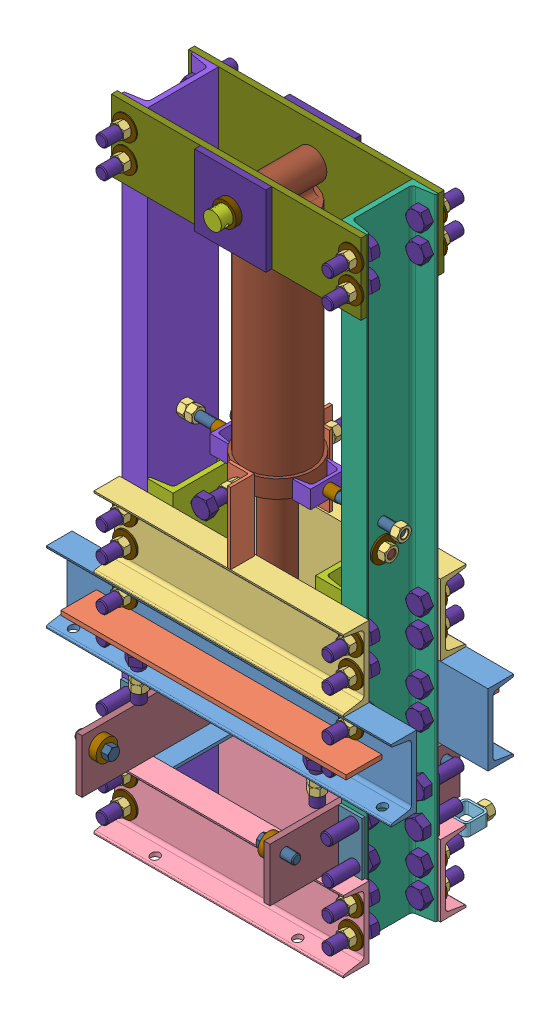
SolidWorks assembly Assem3, configuration Default. Lengths in mm.
Overall size (736.6 1346.2 447.6).
222 component instances, 36 part files, 6 mates.
Components (placement in the parent):
- 01-019-00-0_test-2: 01-019-00-0_test [Default] at (-593.8061 -294.0472 81.4777) size (736.6 1346.2 447.6)
  - 01-013-00-0-1: 01-013-00-0 [Default] at origin size (736.6 169.29 87.3)
    - 01-011-00-0-1: 01-011-00-0 [Default] at origin size (736.6 152.4 54.79)
    - 01-012-00-0-1: 01-012-00-0 [Default] at (-304.8 -4.7625 16.2941) size (609.6 9.53 76.2)
    - hex nut_ai-1: hex nut_ai [HNUT 0.7500-10-D-C] at (190.5 -93.091 -7.5311) x (1 0 0) z (0 -1 0) size (28.57 33 16.89)
    - hex nut_ai-2: hex nut_ai [HNUT 0.7500-10-D-C] at (-190.5 -93.091 -7.5311) x (1 0 0) z (0 -1 0) size (28.57 33 16.89)
  - 01-016-00-0-1: 01-016-00-0 [Default] at (0 -330.2 0) size (533.4 153.99 122.48)
    - 01-014-00-0-2: 01-014-00-0 [Default] at origin size (533.4 152.4 54.79)
    - 01-005-00-0-1: 01-005-00-0 [Default] at (-215.9 63.5 -27.3939) x (0 0 -1) z (0 1 0) size (67.69 50.8 28.57)
      - tube square_ai-1: tube square_ai [PreviewCfg] at origin size (50.8 50.8 25.4)
      - hex nut_ai-1: hex nut_ai [HNUT 0.7500-10-D-C] at (67.691 31.75 0) x (0 0 -1) z (1 0 0) size (28.57 33 16.89)
    - 01-005-00-0-3: 01-005-00-0 [Default] at (215.9 63.5 -27.3939) x (0 0 -1) z (0 -1 0) size (67.69 50.8 28.57)
      - tube square_ai-1: tube square_ai [PreviewCfg] at origin size (50.8 50.8 25.4)
      - hex nut_ai-1: hex nut_ai [HNUT 0.7500-10-D-C] at (67.691 31.75 0) x (0 0 -1) z (1 0 0) size (28.57 33 16.89)
  - 01-014-00-0-6: 01-014-00-0 [Default] at (0 -330.2 207.1878) x (-1 0 0) z (0 0 -1) size (533.4 152.4 54.79)
  - 01-116-00-0-1: 01-116-00-0 [Default] at (234.5817 266.7 103.5939) x (0 -1 0) z (-1 0 0) size (1346.2 152.4 109.58)
    - 01-115-00-0-1: 01-115-00-0 [Default] at origin size (1346.2 152.4 54.79)
    - hex nut_ai-1: hex nut_ai [HNUT 0.7500-10-D-C] at (-82.55 0 44.2849) size (28.57 33 16.89)
    - 01-034-00-0-1: 01-034-00-0 [Default] at (177.8 0 54.7878) size (330.2 152.4 54.79)
  - 01-114-00-0-1: 01-114-00-0 [Default] at (-234.5817 266.7 103.5939) x (0 -1 0) z (1 0 0) size (1346.2 152.4 109.58)
    - 01-015-00-0-2: 01-015-00-0 [Default] at origin size (1346.2 152.4 54.79)
    - hex nut_ai-1: hex nut_ai [HNUT 0.7500-10-D-C] at (-82.55 0 44.2849) size (28.57 33 16.89)
    - 01-034-00-0-1: 01-034-00-0 [Default] at (177.8 0 54.7878) size (330.2 152.4 54.79)
  - 01-013-00-0-2: 01-013-00-0 [Default] at (0 0 207.1878) x (-1 0 0) z (0 0 -1) size (736.6 169.29 87.3)
    - 01-011-00-0-1: 01-011-00-0 [Default] at origin size (736.6 152.4 54.79)
    - 01-012-00-0-1: 01-012-00-0 [Default] at (-304.8 -4.7625 16.2941) size (609.6 9.53 76.2)
    - hex nut_ai-1: hex nut_ai [HNUT 0.7500-10-D-C] at (190.5 -93.091 -7.5311) x (1 0 0) z (0 -1 0) size (28.57 33 16.89)
    - hex nut_ai-2: hex nut_ai [HNUT 0.7500-10-D-C] at (-190.5 -93.091 -7.5311) x (1 0 0) z (0 -1 0) size (28.57 33 16.89)
  - RM3-2RS-1: RM3-2RS [Default] at (173.0078 -171.45 -42.4561) x (1 0 0) z (0 -0.000451 1) size (15.88 50.64 50.64)
  - RM3-2RS-2: RM3-2RS [Default] at (173.0078 -171.45 300.4439) x (1 0 0) z (0 -0.000451 1) size (15.88 50.64 50.64)
  - hex bolt_am_Smaller-6: hex bolt_am_Smaller [PreviewCfg] at (158.0078 -171.45 -42.4561) size (75 27.71 24)
  - hex bolt_am_Smaller-7: hex bolt_am_Smaller [PreviewCfg] at (158.0078 -171.45 300.4439) size (75 27.71 24)
  - RM3-2RS-3: RM3-2RS [Default] at (-173.0078 -171.45 -42.4561) x (-1 0 0) z (0 0.924397 0.381433) size (15.88 50.64 50.64)
  - hex bolt_am_Smaller-8: hex bolt_am_Smaller [PreviewCfg] at (-158.0078 -171.45 300.4439) x (-1 0 0) z (0 -0.23868 0.971098) size (75 27.71 24)
  - hex bolt_am_Smaller-9: hex bolt_am_Smaller [PreviewCfg] at (-158.0078 -171.45 -42.4561) x (-1 0 0) z (0 0.924225 0.381849) size (75 27.71 24)
  - RM3-2RS-4: RM3-2RS [Default] at (-173.0078 -171.45 300.4439) x (-1 0 0) z (0 0.668301 -0.743891) size (15.88 50.64 50.64)
  - 01-039-00-0-1: 01-039-00-0 [Default] at (-5.0705 831.85 103.5939) x (-1 0 0) z (0 0 1) size (254 946.15 152.4)
    - PMC-21012-1: PMC-21012 [Default] at origin size (158.75 946.15 152.4)
    - 01-035-00-0-1: 01-035-00-0 [Default] at (-127 857.25 50.8) size (254 25.4 101.6)
    - 01-040-00-0-1: 01-040-00-0 [Default] at (57.15 831.85 -31.75) x (0 0 1) z (-1 0 0) size (63.5 25.4 25.4)
    - 01-040-00-0-2: 01-040-00-0 [Default] at (-57.15 831.85 31.75) x (0 0 -1) z (1 0 0) size (63.5 25.4 25.4)
    - hex nut_ai-1: hex nut_ai [HNUT 0.7500-10-D-C] at (-112.7125 840.359 -42.5511) x (1 0 0) z (0 -1 0) size (28.57 33 16.89)
    - 01-120-00-0-1: 01-120-00-0 [Default] at (-44.45 850.9 0) x (0 -1 0) z (0 0 1) size (38.1 88.9 38.1)
  - 01-038-00-0-1: 01-038-00-0 [Default] at (-157.4705 -76.2 179.7939) size (304.8 82.55 152.4)
    - 01-036-00-0-1: 01-036-00-0 [Default] at origin size (304.8 25.4 152.4)
    - 01-037-00-0-1: 01-037-00-0 [Default] at (50.8 19.05 -76.2) size (19.05 63.5 19.05)
    - 01-037-00-0-2: 01-037-00-0 [Default] at (254 19.05 -76.2) size (19.05 63.5 19.05)
  - hex bolt_ai-1: hex bolt_ai [PreviewCfg] at (-190.5 -39.37 214.7189) x (0 -1 0) z (1 0 0) size (93.98 43.99 38.1)
  - hex bolt_ai-2: hex bolt_ai [PreviewCfg] at (190.5 -39.37 214.7189) x (0 -1 0) z (1 0 0) size (93.98 43.99 38.1)
  - hex bolt_ai-3: hex bolt_ai [PreviewCfg] at (190.5 -39.37 -7.5311) x (0 -1 0) z (1 0 0) size (93.98 43.99 38.1)
  - hex bolt_ai-4: hex bolt_ai [PreviewCfg] at (-190.5 -39.37 -7.5311) x (0 -1 0) z (1 0 0) size (93.98 43.99 38.1)
  - hex bolt_ai-5: hex bolt_ai [PreviewCfg] at (241.3 -300.0375 56.4658) x (0 0 -1) z (0 1 0) size (93.98 43.99 38.1)
  - hex nut_ai-3: hex nut_ai [HNUT 0.7500-10-D-C] at (241.3 -300.0375 12.5349) x (0.998531 -0.05419 0) z (0 0 1) size (28.57 33 16.89)
  - WASHER 0.7500-WIDE-3: WASHER 0.7500-WIDE [Default] at (241.3 -300.0375 12.5349) size (50.8 50.8 3.76)
  - WASHER 0.7500-WIDE-32: WASHER 0.7500-WIDE [Default] at (241.3 -360.3625 12.5349) size (50.8 50.8 3.76)
  - hex nut_ai-28: hex nut_ai [HNUT 0.7500-10-D-C] at (241.3 -360.3625 12.5349) size (28.57 33 16.89)
  - hex bolt_ai-33: hex bolt_ai [PreviewCfg] at (241.3 -360.3625 56.4658) x (0 0 -1) z (0.005072 0.999987 0) size (93.98 43.99 38.1)
  - WASHER 0.7500-WIDE-34: WASHER 0.7500-WIDE [Default] at (241.3 -30.1625 12.5349) size (50.8 50.8 3.76)
  - hex nut_ai-30: hex nut_ai [HNUT 0.7500-10-D-C] at (241.3 -30.1625 -4.3561) x (0.923728 0.383049 0) z (0 0 -1) size (28.57 33 16.89)
  - hex bolt_ai-35: hex bolt_ai [PreviewCfg] at (241.3 -30.1625 56.4658) x (0 0 -1) z (0 1 0) size (93.98 43.99 38.1)
  - hex nut_ai-32: hex nut_ai [HNUT 0.7500-10-D-C] at (241.3 30.1625 -4.3561) x (0.923728 0.383049 0) z (0 0 -1) size (28.57 33 16.89)
  - WASHER 0.7500-WIDE-36: WASHER 0.7500-WIDE [Default] at (241.3 30.1625 12.5349) size (50.8 50.8 3.76)
  - hex bolt_ai-37: hex bolt_ai [PreviewCfg] at (241.3 30.1625 56.4658) x (0 0 -1) z (0 1 0) size (93.98 43.99 38.1)
  - hex nut_ai-34: hex nut_ai [HNUT 0.7500-10-D-C] at (241.3 122.2375 -4.3561) x (0.923728 0.383049 0) z (0 0 -1) size (28.57 33 16.89)
  - hex bolt_ai-39: hex bolt_ai [PreviewCfg] at (241.3 122.2375 56.4658) x (0 0 -1) z (0 1 0) size (93.98 43.99 38.1)
  - hex nut_ai-36: hex nut_ai [HNUT 0.7500-10-D-C] at (241.3 182.5625 -4.3561) x (0.923728 0.383049 0) z (0 0 -1) size (28.57 33 16.89)
  - WASHER 0.7500-WIDE-38: WASHER 0.7500-WIDE [Default] at (241.3 182.5625 12.5349) size (50.8 50.8 3.76)
  - hex bolt_ai-41: hex bolt_ai [PreviewCfg] at (241.3 182.5625 56.4658) x (0 0 -1) z (0 1 0) size (93.98 43.99 38.1)
  - WASHER 0.7500-WIDE-40: WASHER 0.7500-WIDE [Default] at (241.3 122.2375 12.5349) size (50.8 50.8 3.76)
  - hex nut_ai-38: hex nut_ai [HNUT 0.7500-10-D-C] at (241.3 833.4375 -4.3561) x (0.923728 0.383049 0) z (0 0 -1) size (28.57 33 16.89)
  - hex bolt_ai-43: hex bolt_ai [PreviewCfg] at (241.3 833.4375 56.4658) x (0 0 -1) z (0 1 0) size (93.98 43.99 38.1)
  - hex nut_ai-40: hex nut_ai [HNUT 0.7500-10-D-C] at (241.3 893.7625 -4.3561) x (0.923728 0.383049 0) z (0 0 -1) size (28.57 33 16.89)
  - WASHER 0.7500-WIDE-42: WASHER 0.7500-WIDE [Default] at (241.3 893.7625 12.5349) size (50.8 50.8 3.76)
  - hex bolt_ai-45: hex bolt_ai [PreviewCfg] at (241.3 893.7625 56.4658) x (0 0 -1) z (0 1 0) size (93.98 43.99 38.1)
  - WASHER 0.7500-WIDE-44: WASHER 0.7500-WIDE [Default] at (241.3 833.4375 12.5349) size (50.8 50.8 3.76)
  - WASHER 0.7500-WIDE-46: WASHER 0.7500-WIDE [Default] at (241.3 -360.3625 190.8937) size (50.8 50.8 3.76)
  - hex nut_ai-42: hex nut_ai [HNUT 0.7500-10-D-C] at (241.3 -360.3625 211.5439) size (28.57 33 16.89)
  - hex bolt_ai-47: hex bolt_ai [PreviewCfg] at (241.3 -360.3625 150.722) x (0 0 1) z (-0.381849 -0.924225 0) size (93.98 43.99 38.1)
  - hex nut_ai-44: hex nut_ai [HNUT 0.7500-10-D-C] at (241.3 -300.0375 211.5439) size (28.57 33 16.89)
  - hex bolt_ai-49: hex bolt_ai [PreviewCfg] at (241.3 -300.0375 150.722) x (0 0 1) z (-0.381849 -0.924225 0) size (93.98 43.99 38.1)
  - WASHER 0.7500-WIDE-48: WASHER 0.7500-WIDE [Default] at (241.3 -300.0375 190.8937) size (50.8 50.8 3.76)
  - hex nut_ai-46: hex nut_ai [HNUT 0.7500-10-D-C] at (241.3 -30.1625 211.5439) size (28.57 33 16.89)
  - hex bolt_ai-51: hex bolt_ai [PreviewCfg] at (241.3 -30.1625 150.722) x (0 0 1) z (-0.381849 -0.924225 0) size (93.98 43.99 38.1)
  - hex nut_ai-48: hex nut_ai [HNUT 0.7500-10-D-C] at (241.3 30.1625 211.5439) size (28.57 33 16.89)
  - hex bolt_ai-53: hex bolt_ai [PreviewCfg] at (241.3 30.1625 150.722) x (0 0 1) z (-0.381849 -0.924225 0) size (93.98 43.99 38.1)
  - WASHER 0.7500-WIDE-50: WASHER 0.7500-WIDE [Default] at (241.3 30.1625 190.8937) size (50.8 50.8 3.76)
  - WASHER 0.7500-WIDE-52: WASHER 0.7500-WIDE [Default] at (241.3 -30.1625 190.8937) size (50.8 50.8 3.76)
  - hex nut_ai-50: hex nut_ai [HNUT 0.7500-10-D-C] at (241.3 122.2375 211.5439) size (28.57 33 16.89)
  - hex bolt_ai-55: hex bolt_ai [PreviewCfg] at (241.3 122.2375 150.722) x (0 0 1) z (-0.381849 -0.924225 0) size (93.98 43.99 38.1)
  - hex nut_ai-52: hex nut_ai [HNUT 0.7500-10-D-C] at (241.3 182.5625 211.5439) size (28.57 33 16.89)
  - hex bolt_ai-57: hex bolt_ai [PreviewCfg] at (241.3 182.5625 150.722) x (0 0 1) z (-0.381849 -0.924225 0) size (93.98 43.99 38.1)
  - WASHER 0.7500-WIDE-54: WASHER 0.7500-WIDE [Default] at (241.3 182.5625 190.8937) size (50.8 50.8 3.76)
  - WASHER 0.7500-WIDE-56: WASHER 0.7500-WIDE [Default] at (241.3 122.2375 190.8937) size (50.8 50.8 3.76)
  - hex nut_ai-54: hex nut_ai [HNUT 0.7500-10-D-C] at (241.3 833.4375 211.5439) size (28.57 33 16.89)
  - hex bolt_ai-59: hex bolt_ai [PreviewCfg] at (241.3 833.4375 150.722) x (0 0 1) z (-0.381849 -0.924225 0) size (93.98 43.99 38.1)
  - hex nut_ai-56: hex nut_ai [HNUT 0.7500-10-D-C] at (241.3 893.7625 211.5439) size (28.57 33 16.89)
  - hex bolt_ai-61: hex bolt_ai [PreviewCfg] at (241.3 893.7625 150.722) x (0 0 1) z (-0.381849 -0.924225 0) size (93.98 43.99 38.1)
  - WASHER 0.7500-WIDE-58: WASHER 0.7500-WIDE [Default] at (241.3 893.7625 190.8937) size (50.8 50.8 3.76)
  - WASHER 0.7500-WIDE-60: WASHER 0.7500-WIDE [Default] at (241.3 833.4375 190.8937) size (50.8 50.8 3.76)
  - hex bolt_ai-32: hex bolt_ai [PreviewCfg] at (-241.3 -300.0375 56.4658) x (0 0 -1) z (0 -1 0) size (93.98 43.99 38.1)
  - hex nut_ai-27: hex nut_ai [HNUT 0.7500-10-D-C] at (-241.3 -300.0375 -4.3527) x (-0.998531 -0.05419 0) z (0 0 -1) size (28.57 33 16.89)
  - WASHER 0.7500-WIDE-31: WASHER 0.7500-WIDE [Default] at (-241.3 -300.0375 16.2941) x (-1 0 0) z (0 0 -1) size (50.8 50.8 3.76)
  - WASHER 0.7500-WIDE-33: WASHER 0.7500-WIDE [Default] at (-241.3 -360.3625 16.2941) x (-1 0 0) z (0 0 -1) size (50.8 50.8 3.76)
  - hex nut_ai-29: hex nut_ai [HNUT 0.7500-10-D-C] at (-241.3 -360.3625 -4.3527) x (-1 0 0) z (0 0 -1) size (28.57 33 16.89)
  - hex bolt_ai-34: hex bolt_ai [PreviewCfg] at (-241.3 -360.3625 56.4658) x (0 0 -1) z (0.005072 -0.999987 0) size (93.98 43.99 38.1)
  - WASHER 0.7500-WIDE-35: WASHER 0.7500-WIDE [Default] at (-241.3 -30.1625 16.2941) x (-1 0 0) z (0 0 -1) size (50.8 50.8 3.76)
  - hex nut_ai-31: hex nut_ai [HNUT 0.7500-10-D-C] at (-241.3 -30.1625 12.5315) x (-0.923728 0.383049 0) z (0 0 1) size (28.57 33 16.89)
  - hex bolt_ai-36: hex bolt_ai [PreviewCfg] at (-241.3 -30.1625 56.4658) x (0 0 -1) z (0 -1 0) size (93.98 43.99 38.1)
  - hex nut_ai-33: hex nut_ai [HNUT 0.7500-10-D-C] at (-241.3 30.1625 12.5315) x (-0.923728 0.383049 0) z (0 0 1) size (28.57 33 16.89)
  - WASHER 0.7500-WIDE-37: WASHER 0.7500-WIDE [Default] at (-241.3 30.1625 16.2941) x (-1 0 0) z (0 0 -1) size (50.8 50.8 3.76)
  - hex bolt_ai-38: hex bolt_ai [PreviewCfg] at (-241.3 30.1625 56.4658) x (0 0 -1) z (0 -1 0) size (93.98 43.99 38.1)
  - hex nut_ai-35: hex nut_ai [HNUT 0.7500-10-D-C] at (-241.3 122.2375 12.5315) x (-0.923728 0.383049 0) z (0 0 1) size (28.57 33 16.89)
  - hex bolt_ai-40: hex bolt_ai [PreviewCfg] at (-241.3 122.2375 56.4658) x (0 0 -1) z (0 -1 0) size (93.98 43.99 38.1)
  - hex nut_ai-37: hex nut_ai [HNUT 0.7500-10-D-C] at (-241.3 182.5625 12.5315) x (-0.923728 0.383049 0) z (0 0 1) size (28.57 33 16.89)
  - WASHER 0.7500-WIDE-39: WASHER 0.7500-WIDE [Default] at (-241.3 182.5625 16.2941) x (-1 0 0) z (0 0 -1) size (50.8 50.8 3.76)
  - hex bolt_ai-42: hex bolt_ai [PreviewCfg] at (-241.3 182.5625 56.4658) x (0 0 -1) z (0 -1 0) size (93.98 43.99 38.1)
  - WASHER 0.7500-WIDE-41: WASHER 0.7500-WIDE [Default] at (-241.3 122.2375 16.2941) x (-1 0 0) z (0 0 -1) size (50.8 50.8 3.76)
  - hex nut_ai-39: hex nut_ai [HNUT 0.7500-10-D-C] at (-241.3 833.4375 12.5315) x (-0.923728 0.383049 0) z (0 0 1) size (28.57 33 16.89)
  - hex bolt_ai-44: hex bolt_ai [PreviewCfg] at (-241.3 833.4375 56.4658) x (0 0 -1) z (0 -1 0) size (93.98 43.99 38.1)
  - hex nut_ai-41: hex nut_ai [HNUT 0.7500-10-D-C] at (-241.3 893.7625 12.5315) x (-0.923728 0.383049 0) z (0 0 1) size (28.57 33 16.89)
  - WASHER 0.7500-WIDE-43: WASHER 0.7500-WIDE [Default] at (-241.3 893.7625 16.2941) x (-1 0 0) z (0 0 -1) size (50.8 50.8 3.76)
  - hex bolt_ai-46: hex bolt_ai [PreviewCfg] at (-241.3 893.7625 56.4658) x (0 0 -1) z (0 -1 0) size (93.98 43.99 38.1)
  - WASHER 0.7500-WIDE-45: WASHER 0.7500-WIDE [Default] at (-241.3 833.4375 16.2941) x (-1 0 0) z (0 0 -1) size (50.8 50.8 3.76)
  - WASHER 0.7500-WIDE-47: WASHER 0.7500-WIDE [Default] at (-241.3 -360.3625 194.6529) x (-1 0 0) z (0 0 -1) size (50.8 50.8 3.76)
  - hex nut_ai-43: hex nut_ai [HNUT 0.7500-10-D-C] at (-241.3 -360.3625 194.6563) x (-1 0 0) z (0 0 -1) size (28.57 33 16.89)
  - hex bolt_ai-48: hex bolt_ai [PreviewCfg] at (-241.3 -360.3625 150.722) x (0 0 1) z (-0.381849 0.924225 0) size (93.98 43.99 38.1)
  - hex nut_ai-45: hex nut_ai [HNUT 0.7500-10-D-C] at (-241.3 -300.0375 194.6563) x (-1 0 0) z (0 0 -1) size (28.57 33 16.89)
  - hex bolt_ai-50: hex bolt_ai [PreviewCfg] at (-241.3 -300.0375 150.722) x (0 0 1) z (-0.381849 0.924225 0) size (93.98 43.99 38.1)
  - WASHER 0.7500-WIDE-49: WASHER 0.7500-WIDE [Default] at (-241.3 -300.0375 194.6529) x (-1 0 0) z (0 0 -1) size (50.8 50.8 3.76)
  - hex nut_ai-47: hex nut_ai [HNUT 0.7500-10-D-C] at (-241.3 -30.1625 194.6563) x (-1 0 0) z (0 0 -1) size (28.57 33 16.89)
  - hex bolt_ai-52: hex bolt_ai [PreviewCfg] at (-241.3 -30.1625 150.722) x (0 0 1) z (-0.381849 0.924225 0) size (93.98 43.99 38.1)
  - hex nut_ai-49: hex nut_ai [HNUT 0.7500-10-D-C] at (-241.3 30.1625 194.6563) x (-1 0 0) z (0 0 -1) size (28.57 33 16.89)
  - hex bolt_ai-54: hex bolt_ai [PreviewCfg] at (-241.3 30.1625 150.722) x (0 0 1) z (-0.381849 0.924225 0) size (93.98 43.99 38.1)
  - WASHER 0.7500-WIDE-51: WASHER 0.7500-WIDE [Default] at (-241.3 30.1625 194.6529) x (-1 0 0) z (0 0 -1) size (50.8 50.8 3.76)
  - WASHER 0.7500-WIDE-53: WASHER 0.7500-WIDE [Default] at (-241.3 -30.1625 194.6529) x (-1 0 0) z (0 0 -1) size (50.8 50.8 3.76)
  - hex nut_ai-51: hex nut_ai [HNUT 0.7500-10-D-C] at (-241.3 122.2375 194.6563) x (-1 0 0) z (0 0 -1) size (28.57 33 16.89)
  - hex bolt_ai-56: hex bolt_ai [PreviewCfg] at (-241.3 122.2375 150.722) x (0 0 1) z (-0.381849 0.924225 0) size (93.98 43.99 38.1)
  - hex nut_ai-53: hex nut_ai [HNUT 0.7500-10-D-C] at (-241.3 182.5625 194.6563) x (-1 0 0) z (0 0 -1) size (28.57 33 16.89)
  - hex bolt_ai-58: hex bolt_ai [PreviewCfg] at (-241.3 182.5625 150.722) x (0 0 1) z (-0.381849 0.924225 0) size (93.98 43.99 38.1)
  - WASHER 0.7500-WIDE-55: WASHER 0.7500-WIDE [Default] at (-241.3 182.5625 194.6529) x (-1 0 0) z (0 0 -1) size (50.8 50.8 3.76)
  - WASHER 0.7500-WIDE-57: WASHER 0.7500-WIDE [Default] at (-241.3 122.2375 194.6529) x (-1 0 0) z (0 0 -1) size (50.8 50.8 3.76)
  - hex nut_ai-55: hex nut_ai [HNUT 0.7500-10-D-C] at (-241.3 833.4375 194.6563) x (-1 0 0) z (0 0 -1) size (28.57 33 16.89)
  - hex bolt_ai-60: hex bolt_ai [PreviewCfg] at (-241.3 833.4375 150.722) x (0 0 1) z (-0.381849 0.924225 0) size (93.98 43.99 38.1)
  - hex nut_ai-57: hex nut_ai [HNUT 0.7500-10-D-C] at (-241.3 893.7625 194.6563) x (-1 0 0) z (0 0 -1) size (28.57 33 16.89)
  - hex bolt_ai-62: hex bolt_ai [PreviewCfg] at (-241.3 893.7625 150.722) x (0 0 1) z (-0.381849 0.924225 0) size (93.98 43.99 38.1)
  - WASHER 0.7500-WIDE-59: WASHER 0.7500-WIDE [Default] at (-241.3 893.7625 194.6529) x (-1 0 0) z (0 0 -1) size (50.8 50.8 3.76)
  - WASHER 0.7500-WIDE-61: WASHER 0.7500-WIDE [Default] at (-241.3 833.4375 194.6529) x (-1 0 0) z (0 0 -1) size (50.8 50.8 3.76)
  - 01-107-00-0-1: 01-107-00-0 [Default] at (-207.1878 -257.175 103.5939) x (0 -1 0) z (0 0 1) size (50.8 50.8 152.4)
  - 01-107-00-0-2: 01-107-00-0 [Default] at (207.1878 -257.175 103.5939) x (0 -1 0) z (0 0 -1) size (50.8 50.8 152.4)
  - 01-101-00-0-1: 01-101-00-0 [Default] at (25.4 381 183.7817) x (0 0 1) z (1 0 0) size (54.79 304.8 533.4)
    - 01-100-00-0-1: 01-100-00-0 [Default] at origin size (50.8 152.4 50.8)
    - hex nut_ai-1: hex nut_ai [HNUT 0.7500-10-D-C] at (23.241 31.75 -25.4) x (0 0 -1) z (1 0 0) size (28.57 33 16.89)
    - 01-108-00-0-2: 01-108-00-0 [Default] at (23.4061 228.6 -25.4) x (0 0 -1) z (-1 0 0) size (533.4 152.4 54.79)
  - 01-101-00-0-2: 01-101-00-0 [Default] at (-25.4 381 23.4061) x (0 0 -1) z (-1 0 0) size (54.79 304.8 533.4)
    - 01-100-00-0-1: 01-100-00-0 [Default] at origin size (50.8 152.4 50.8)
    - hex nut_ai-1: hex nut_ai [HNUT 0.7500-10-D-C] at (23.241 31.75 -25.4) x (0 0 -1) z (1 0 0) size (28.57 33 16.89)
    - 01-108-00-0-2: 01-108-00-0 [Default] at (23.4061 228.6 -25.4) x (0 0 -1) z (-1 0 0) size (533.4 152.4 54.79)
  - hex nut_ai-58: hex nut_ai [HNUT 0.7500-10-D-C] at (0 349.25 207.0227) x (0 1 0) z (0 0 -1) size (28.57 33 16.89)
  - hex bolt_ai-63: hex bolt_ai [PreviewCfg] at (0 349.25 273.7739) x (0 0 -1) z (0 -1 0) size (93.98 43.99 38.1)
  - hex nut_ai-59: hex nut_ai [HNUT 0.7500-10-D-C] at (0 349.25 0.1651) x (0.924225 -0.381849 0) z (0 0 1) size (28.57 33 16.89)
  - hex bolt_ai-64: hex bolt_ai [PreviewCfg] at (0 349.25 -66.5861) x (0 0 1) z (-0.924225 0.381849 0) size (93.98 43.99 38.1)
  - hex nut_ai-60: hex nut_ai [HNUT 0.7500-10-D-C] at (-106.6705 -8.509 103.5939) x (1 0 0) z (0 1 0) size (28.57 33 16.89)
  - hex nut_ai-61: hex nut_ai [HNUT 0.7500-10-D-C] at (96.5295 -8.509 103.5939) x (1 0 0) z (0 1 0) size (28.57 33 16.89)
  - 01-094-00-0-1: 01-094-00-0 [Default] at (126.8614 329.0672 93.8592) x (0 0 1) z (0 1 0) size (26.02 26.02 393.7)
    - 01-093-00-0-1: 01-093-00-0 [Default] at (-45.5164 -22.3944 39.2328) size (25.4 6.35 355.6)
    - TROD 0.7500-1x1.25-1: TROD 0.7500-1x1.25 [Default] at (-32.8164 -19.2194 -316.3672) x (0.5 -0.866025 0) z (0.866025 0.5 0) size (19.05 38.1 19.05)
  - 01-095-00-0-1: 01-095-00-0 [Default] at (117.167 342.9 61.0428) x (0 -0.957416 0.288712) z (-1 0 0) size (12.7 12.7 6.35)
  - 01-095-00-0-2: 01-095-00-0 [Default] at (117.167 292.1 61.0428) x (0 -0.957416 0.288712) z (-1 0 0) size (12.7 12.7 6.35)
  - 01-095-00-0-3: 01-095-00-0 [Default] at (117.167 63.5 61.0428) x (0 -0.957416 0.288712) z (-1 0 0) size (12.7 12.7 6.35)
  - hex nut_ai-62: hex nut_ai [HNUT 0.7500-10-D-C] at (190.5 -109.982 214.7189) x (1 0 0) z (0 -1 0) size (28.57 33 16.89)
  - hex nut_ai-63: hex nut_ai [HNUT 0.7500-10-D-C] at (-190.5 -109.982 214.7189) x (1 0 0) z (0 -1 0) size (28.57 33 16.89)
  - hex nut_ai-64: hex nut_ai [HNUT 0.7500-10-D-C] at (-190.5 -109.982 -7.5311) x (1 0 0) z (0 -1 0) size (28.57 33 16.89)
  - hex nut_ai-65: hex nut_ai [HNUT 0.7500-10-D-C] at (190.5 -109.982 -7.5311) x (1 0 0) z (0 -1 0) size (28.57 33 16.89)
  - 01-103-00-0-1: 01-103-00-0 [Default] at (-4.7244 863.6 -36.1061) x (0.402511 0.915415 0) z (0.915415 -0.402511 0) size (38.1 279.4 38.1)
  - 01-113-00-0-1: 01-113-00-0 [Default] at (7.4387 299.9526 109.143) x (1 0 0) z (0 1 0) size (63.45 76.2 38.1)
    - 01-112-00-0-1: 01-112-00-0 [Default] at (-117.0124 -34.5535 49.2974) size (38.05 76.2 38.1)
    - 01-111-00-0-1: 01-111-00-0 [Default] at (-142.4124 3.5465 49.2974) x (0 -1 0) z (0 0 1) size (23.81 25.4 23.81)
  - 01-113-00-0-2: 01-113-00-0 [Default] at (-15.6085 398.5474 105.3144) x (-1 0 0) z (0 -1 0) size (63.45 76.2 38.1)
    - 01-112-00-0-1: 01-112-00-0 [Default] at (-117.0124 -34.5535 49.2974) size (38.05 76.2 38.1)
    - 01-111-00-0-1: 01-111-00-0 [Default] at (-142.4124 3.5465 49.2974) x (0 -1 0) z (0 0 1) size (23.81 25.4 23.81)
  - hex nut_ai-66: hex nut_ai [HNUT 0.7500-10-D-C] at (173.4058 349.25 103.5939) x (0 0 1) z (-1 0 0) size (28.57 33 16.89)
  - hex nut_ai-67: hex nut_ai [HNUT 0.7500-10-D-C] at (-173.4058 349.25 103.5939) x (0 0 -1) z (1 0 0) size (28.57 33 16.89)
  - 01-117-00-0-1: 01-117-00-0 [Default] at (101.4039 349.25 103.5939) x (0 -1 0) z (0 0 1) size (28.57 165.1 33)
    - TROD 0.7500-1x6.25-1: TROD 0.7500-1x6.25 [Default] at origin size (19.05 158.75 19.05)
    - hex nut_ai-1: hex nut_ai [HNUT 0.7500-10-D-C] at (0 165.1 0) x (1 0 0) z (0 1 0) size (28.57 33 16.89)
  - 01-117-00-0-2: 01-117-00-0 [Default] at (-109.5737 349.25 103.5939) x (0 1 0) z (0 0 1) size (28.57 165.1 33)
    - TROD 0.7500-1x6.25-1: TROD 0.7500-1x6.25 [Default] at origin size (19.05 158.75 19.05)
    - hex nut_ai-1: hex nut_ai [HNUT 0.7500-10-D-C] at (0 165.1 0) x (1 0 0) z (0 1 0) size (28.57 33 16.89)
  - 01-097-00-0-1: 01-097-00-0 [Default] at (237.3376 298.45 103.5939) x (0 -0.797124 0.603815) z (0 -0.603815 -0.797124) size (141.46 99.52 78.97)
    - TROD 0.7500-1x3.5-1: TROD 0.7500-1x3.5 [Default] at origin size (19.05 88.9 19.05)
    - 01-096-00-0-1: 01-096-00-0 [Default] at (-127.635 93.6625 -64.2073) x (0.119593 0.96382 -0.238218) z (0.432432 -0.266552 -0.861367) size (9.53 152.4 9.53)
  - hex nut_ai-68: hex nut_ai [HNUT 0.7500-10-D-C] at (203.4286 298.45 103.5939) x (0 0 -1) z (1 0 0) size (28.57 33 16.89)
  - WASHER 0.7500-WIDE-62: WASHER 0.7500-WIDE [Default] at (203.4286 298.45 103.5939) x (0 0 -1) z (1 0 0) size (50.8 50.8 3.76)
  - hex nut_ai-69: hex nut_ai [HNUT 0.7500-10-D-C] at (238.9378 298.45 103.5939) x (0 0 -1) z (1 0 0) size (28.57 33 16.89)
  - WASHER 0.7500-WIDE-63: WASHER 0.7500-WIDE [Default] at (222.0468 298.45 103.5939) x (0 0 -1) z (-1 0 0) size (50.8 50.8 3.76)
  - hex nut_ai-70: hex nut_ai [HNUT 0.7500-10-D-C] at (107.642 8.382 61.0428) x (1 0 0) z (0 1 0) size (28.57 33 16.89)
  - Cam_Support_Ass-1: Cam_Support_Ass [Default] at (-231.8482 -246.6552 110.6361) x (0 0 -1) z (0 1 0) size (447.04 64.13 152.4)
    - 01-020-00-0-1: 01-020-00-0 [Default] at (-221.5578 -37.3604 106.9552) size (447.04 13.97 152.4)
    - Cam Support Tab-1: Cam Support Tab [Default] at (-75.5078 -24.6604 106.9552) x (0 1 0) z (-1 0 0) size (50.8 114.3 6.35)
    - Cam Support Tab-2: Cam Support Tab [Default] at (83.2422 -24.6604 106.9552) x (0 1 0) z (-1 0 0) size (50.8 114.3 6.35)
  - Cam_Support_Ass_3-1: Cam_Support_Ass_3 [Default] at (205.4753 -251.743 123.9765) x (0 0 1) z (0 1 0) size (447.04 64.13 152.4)
    - 01-020-00-0-1: 01-020-00-0 [Default] at (-198.1826 -10.9875 112.043) size (447.04 13.97 152.4)
    - Cam Support Tab-1: Cam Support Tab [Default] at (-102.9326 1.7125 112.043) x (0 1 0) z (-1 0 0) size (50.8 114.3 6.35)
    - Cam Support Tab-2: Cam Support Tab [Default] at (55.8174 1.7125 112.043) x (0 1 0) z (-1 0 0) size (50.8 114.3 6.35)
  - hex bolt_ai-65: hex bolt_ai [PreviewCfg] at (238.9378 -234.95 56.4658) x (0 0 -1) z (1 0 0) size (93.98 43.99 38.1)
  - hex bolt_ai-67: hex bolt_ai [PreviewCfg] at (241.3191 -158.75 56.4658) x (0 0 -1) z (1 0 0) size (93.98 43.99 38.1)
  - hex bolt_ai-68: hex bolt_ai [PreviewCfg] at (241.3191 -234.95 150.722) x (0 0 1) z (-0.001298 0.999999 0) size (93.98 43.99 38.1)
  - hex bolt_ai-69: hex bolt_ai [PreviewCfg] at (238.9378 -158.75 150.722) x (0 0 1) z (-0.923728 -0.383049 0) size (93.98 43.99 38.1)
  - hex bolt_ai-70: hex bolt_ai [PreviewCfg] at (-241.3191 -234.95 150.722) x (0 0 1) z (-1 0 0) size (93.98 43.99 38.1)
  - hex bolt_ai-71: hex bolt_ai [PreviewCfg] at (-241.3191 -158.75 150.722) x (0 0 1) z (-1 0 0) size (93.98 43.99 38.1)
  - hex bolt_ai-73: hex bolt_ai [PreviewCfg] at (-241.3191 -234.95 56.4658) x (0 0 -1) z (-0.923728 -0.383049 0) size (93.98 43.99 38.1)
  - hex bolt_ai-74: hex bolt_ai [PreviewCfg] at (-241.3191 -158.75 56.4658) x (0 0 -1) z (-0.923728 -0.383049 0) size (93.98 43.99 38.1)
  - WASHER 0.7500-WIDE-80: WASHER 0.7500-WIDE [Default] at (-241.3191 -234.95 186.1439) size (50.8 50.8 3.76)
  - WASHER 0.375-WIDE-3: WASHER 0.375-WIDE [Default] at (194.4878 -171.45 300.4439) size (2.11 25.4 25.4)
- Base Plate Ass-1: Base Plate Ass [Default] at (-548.3089 574.2066 237.9585) size (533.4 152.4 38.1)
  - Base plate update-1: Base plate update [Default] at (-316.9216 -80.8539 23.313) size (533.4 152.4 12.7)
  - Base Plate Support-1: Base Plate Support [Default] at (-126.4216 -80.8539 36.013) size (152.4 152.4 12.7)
  - 01-109-00-0-1: 01-109-00-0 [Default] at (-50.2216 -4.6539 23.313) x (1 0 0) z (0 -1 0) size (50.8 38.1 50.8)
- Base Plate Ass-2: Base Plate Ass [Default] at (-648.7522 574.2066 132.1846) x (-1 0 0) z (0 0 -1) size (533.4 152.4 38.1)
  - Base plate update-1: Base plate update [Default] at (-316.9216 -80.8539 23.313) size (533.4 152.4 12.7)
  - Base Plate Support-1: Base Plate Support [Default] at (-126.4216 -80.8539 36.013) size (152.4 152.4 12.7)
  - 01-109-00-0-1: 01-109-00-0 [Default] at (-50.2216 -4.6539 23.313) x (1 0 0) z (0 -1 0) size (50.8 38.1 50.8)
Mates (geometry in assembly coordinates):
- Coincident3: coincident: plane of 01-019-00-0_test-2/01-114-00-0-1/01-015-00-0-2 through (-852.7337 645.7528 258.7823) normal (0 1 0); plane of Base Plate Ass-1/Base plate update-1 through (-865.2305 645.7528 291.6761) normal (0 1 0)
- Concentric2: concentric: cylinder of 01-019-00-0_test-2/01-103-00-0-1 through (-598.5305 569.5528 324.7716) axis (0 0 -1) radius 19.05; cylinder of Base Plate Ass-1/01-109-00-0-1 through (-598.5305 569.5528 299.3716) axis (0 0 -1) radius 19.05
- Coincident4: coincident anti-aligned: plane of 01-019-00-0_test-2/01-116-00-0-1/01-115-00-0-1 through (-386.6183 -700.4472 261.2716) normal (0 0 1); plane of Base Plate Ass-1/Base plate update-1 through (-865.2305 493.3528 261.2716) normal (0 0 -1)
- Coincident5: coincident: plane of 01-019-00-0_test-2/01-114-00-0-1/01-015-00-0-2 through (-800.9939 -700.4472 108.8716) normal (0 0 -1); plane of Base Plate Ass-2/Base plate update-1 through (-331.8305 493.3528 108.8716) normal (0 0 1)
- Coincident6: coincident: plane of 01-019-00-0_test-2/01-114-00-0-1/01-015-00-0-2 through (-852.7337 645.7528 258.7823) normal (0 1 0); plane of Base Plate Ass-2/Base plate update-1 through (-331.8305 645.7528 96.1716) normal (0 1 0)
- Concentric3: concentric anti-aligned: cylinder of 01-019-00-0_test-2/01-103-00-0-1 through (-598.5305 569.5528 324.7716) axis (0 0 -1) radius 19.05; cylinder of Base Plate Ass-2/01-109-00-0-1 through (-598.5305 569.5528 70.7716) axis (0 0 1) radius 19.05
